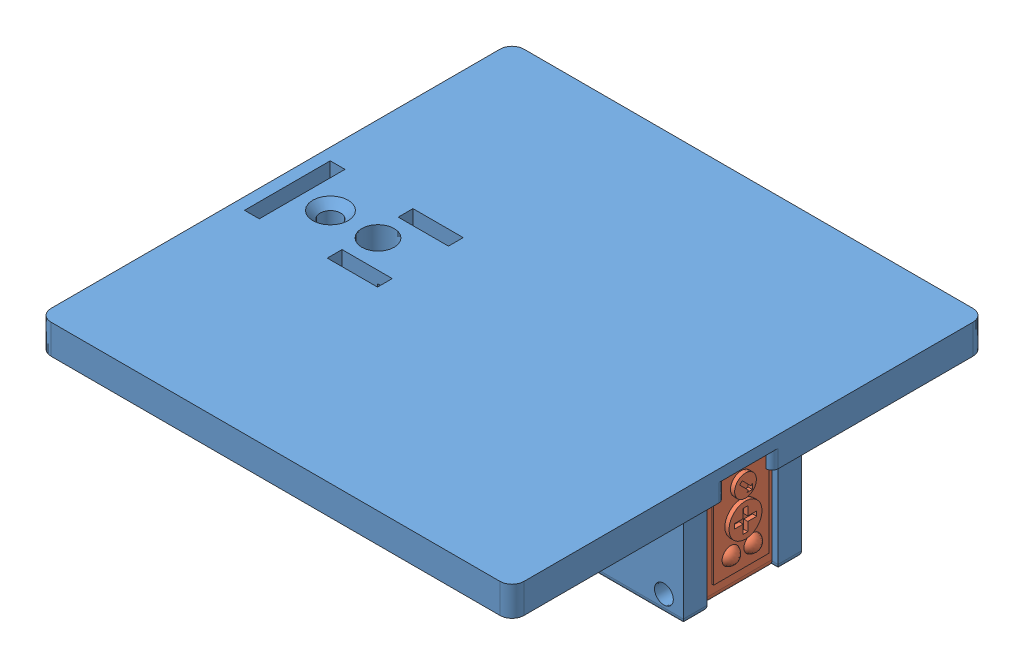
SolidWorks assembly Plaque_top_SICK, configuration Default. Lengths in mm.
Overall size (80 21 80).
2 component instances, 2 part files, 3 mates.
Components (placement in the parent):
- Plaque_top-2: Plaque_top [Default] at origin size (80 21 80)
- SICK WL100-N4439-Bestell-Nr_6028604(0)-1-1: SICK WL100-N4439-Bestell-Nr_6028604(0)-1 [Default] at (50.3 -13 -45.5) x (0 1 0) z (0 0 -1) size (20 42.65 11)
Mates (geometry in assembly coordinates):
- Concentric4: concentric anti-aligned: circle of Plaque_top-2; circle of SICK WL100-N4439-Bestell-Nr_6028604(0)-1-1
- Concentric5: concentric anti-aligned: circle of Plaque_top-2; circle of SICK WL100-N4439-Bestell-Nr_6028604(0)-1-1
- Distance1: distance = 0.5 mm anti-aligned: plane of Plaque_top-2 through (47 0 -46) normal (0 0 1); plane of SICK WL100-N4439-Bestell-Nr_6028604(0)-1-1 through (76.8029 -14.8 -45.5) normal (0 0 -1)
